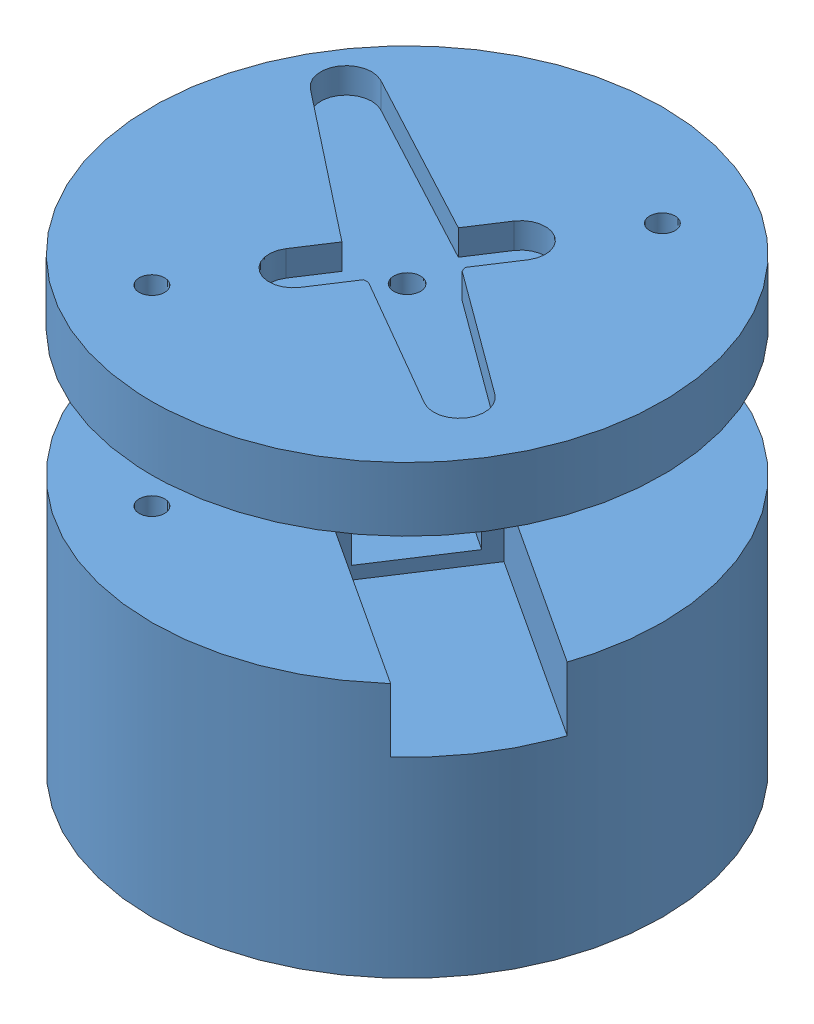
SolidWorks assembly Rocker Motor Servo joint, configuration Default. Lengths in mm.
Overall size (42.09 20.29 45.95).
2 component instances, 2 part files, 3 mates.
Components (placement in the parent):
- Servo_Connector_1-1: Servo_Connector_1 [Default] at (45.2146 17.0562 25.5013) size (40 15 40) (hidden)
- Rocker Motor mount vP-1: Rocker Motor mount vP [Default] at (34.1172 9.0562 36.9899) size (42.09 30 45.95)
Mates (geometry in assembly coordinates):
- Coincident1: coincident anti-aligned: plane of Servo_Connector_1-1 through (19.5635 9.0562 34.5894) normal (0 -1 0); plane of Rocker Motor mount vP-1 through (19.5635 9.0562 34.5894) normal (0 1 0)
- Concentric1: concentric anti-aligned: cylinder of Servo_Connector_1-1 through (11.6602 19.0562 46.6865) axis (0 -1 0) radius 1; cylinder of Rocker Motor mount vP-1 through (11.6602 -5.9438 46.6865) axis (0 1 0) radius 1
- Concentric2: concentric anti-aligned: cylinder of Servo_Connector_1-1 through (27.4669 19.0562 22.4923) axis (0 -1 0) radius 1; cylinder of Rocker Motor mount vP-1 through (27.4669 -5.9438 22.4923) axis (0 1 0) radius 1
